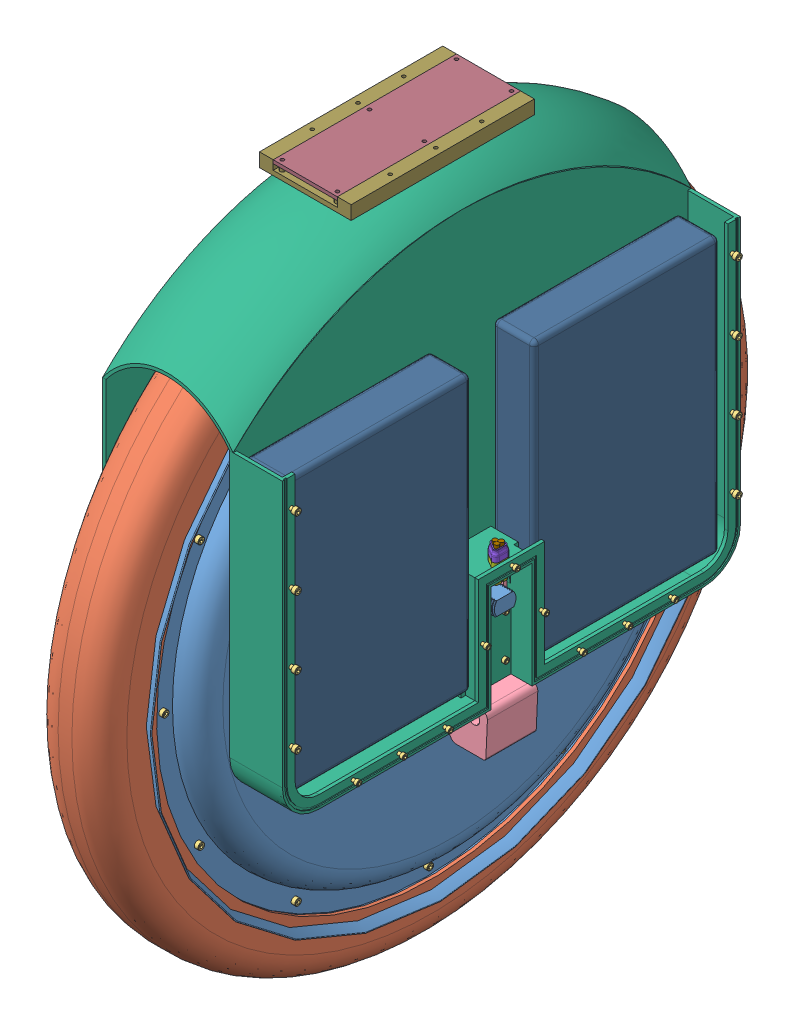
SolidWorks assembly euc0.2, configuration Default. Lengths in mm.
Overall size (364.75 810.04 810.04).
62 component instances, 14 part files, 64 mates.
Components (placement in the parent):
- wheel-1: wheel [Default] at origin size (217.51 810.04 810.04)
  - motor-1: motor [Default] at origin size (188.73 505.83 505.83)
  - tyre-1: tyre [Default] at (-29.8207 0 0) x (1 0 0) z (0 0.587098 0.809516) size (60 580 580)
  - socket head cap screw_ai-1: socket head cap screw_ai [HX-SHCS 0.138-40x0.188x0.188-N] at (29.5052 231 0) x (-1 0 0) z (0 0 -1) size (8.28 5.74 5.74)
  - socket head cap screw_ai-2: socket head cap screw_ai [HX-SHCS 0.138-40x0.188x0.188-N] at (29.5052 200.0519 -115.5) x (-1 0 0) z (0 -0.5 -0.866025) size (8.28 5.74 5.74)
  - socket head cap screw_ai-3: socket head cap screw_ai [HX-SHCS 0.138-40x0.188x0.188-N] at (29.5052 200.0519 115.5) x (-1 0 0) z (0 0.5 -0.866025) size (8.28 5.74 5.74)
  - socket head cap screw_ai-4: socket head cap screw_ai [HX-SHCS 0.138-40x0.188x0.188-N] at (29.5052 115.5 200.0519) x (-1 0 0) z (0 0.866025 -0.5) size (8.28 5.74 5.74)
  - socket head cap screw_ai-5: socket head cap screw_ai [HX-SHCS 0.138-40x0.188x0.188-N] at (29.5052 0 231) x (-1 0 0) z (0 1 0) size (8.28 5.74 5.74)
  - socket head cap screw_ai-6: socket head cap screw_ai [HX-SHCS 0.138-40x0.188x0.188-N] at (29.5052 -115.5 200.0519) x (-1 0 0) z (0 0.866025 0.5) size (8.28 5.74 5.74)
  - socket head cap screw_ai-7: socket head cap screw_ai [HX-SHCS 0.138-40x0.188x0.188-N] at (29.5052 -200.0519 115.5) x (-1 0 0) z (0 0.5 0.866025) size (8.28 5.74 5.74)
  - socket head cap screw_ai-8: socket head cap screw_ai [HX-SHCS 0.138-40x0.188x0.188-N] at (29.5052 -231 0) x (-1 0 0) z (0 0 1) size (8.28 5.74 5.74)
  - socket head cap screw_ai-9: socket head cap screw_ai [HX-SHCS 0.138-40x0.188x0.188-N] at (29.5052 -200.0519 -115.5) x (-1 0 0) z (0 -0.5 0.866025) size (8.28 5.74 5.74)
  - socket head cap screw_ai-10: socket head cap screw_ai [HX-SHCS 0.138-40x0.188x0.188-N] at (29.5052 -115.5 -200.0519) x (-1 0 0) z (0 -0.866025 0.5) size (8.28 5.74 5.74)
  - socket head cap screw_ai-11: socket head cap screw_ai [HX-SHCS 0.138-40x0.188x0.188-N] at (29.5052 0 -231) x (-1 0 0) z (0 -1 0) size (8.28 5.74 5.74)
  - socket head cap screw_ai-12: socket head cap screw_ai [HX-SHCS 0.138-40x0.188x0.188-N] at (29.5052 115.5 -200.0519) x (-1 0 0) z (0 -0.866025 -0.5) size (8.28 5.74 5.74)
  - socket head cap screw_ai-13: socket head cap screw_ai [HX-SHCS 0.138-40x0.188x0.188-N] at (-29.5052 231 0) size (8.28 5.74 5.74)
  - socket head cap screw_ai-14: socket head cap screw_ai [HX-SHCS 0.138-40x0.188x0.188-N] at (-29.5052 200.0519 -115.5) x (1 0 0) z (0 0.5 0.866025) size (8.28 5.74 5.74)
  - socket head cap screw_ai-15: socket head cap screw_ai [HX-SHCS 0.138-40x0.188x0.188-N] at (-29.5052 200.0519 115.5) x (1 0 0) z (0 -0.5 0.866025) size (8.28 5.74 5.74)
  - socket head cap screw_ai-16: socket head cap screw_ai [HX-SHCS 0.138-40x0.188x0.188-N] at (-29.5052 115.5 200.0519) x (1 0 0) z (0 -0.866025 0.5) size (8.28 5.74 5.74)
  - socket head cap screw_ai-17: socket head cap screw_ai [HX-SHCS 0.138-40x0.188x0.188-N] at (-29.5052 0 231) x (1 0 0) z (0 -1 0) size (8.28 5.74 5.74)
  - socket head cap screw_ai-18: socket head cap screw_ai [HX-SHCS 0.138-40x0.188x0.188-N] at (-29.5052 -115.5 200.0519) x (1 0 0) z (0 -0.866025 -0.5) size (8.28 5.74 5.74)
  - socket head cap screw_ai-19: socket head cap screw_ai [HX-SHCS 0.138-40x0.188x0.188-N] at (-29.5052 -200.0519 115.5) x (1 0 0) z (0 -0.5 -0.866025) size (8.28 5.74 5.74)
  - socket head cap screw_ai-20: socket head cap screw_ai [HX-SHCS 0.138-40x0.188x0.188-N] at (-29.5052 -231 0) x (1 0 0) z (0 0 -1) size (8.28 5.74 5.74)
  - socket head cap screw_ai-21: socket head cap screw_ai [HX-SHCS 0.138-40x0.188x0.188-N] at (-29.5052 -200.0519 -115.5) x (1 0 0) z (0 0.5 -0.866025) size (8.28 5.74 5.74)
  - socket head cap screw_ai-22: socket head cap screw_ai [HX-SHCS 0.138-40x0.188x0.188-N] at (-29.5052 -115.5 -200.0519) x (1 0 0) z (0 0.866025 -0.5) size (8.28 5.74 5.74)
  - socket head cap screw_ai-23: socket head cap screw_ai [HX-SHCS 0.138-40x0.188x0.188-N] at (-29.5052 0 -231) x (1 0 0) z (0 1 0) size (8.28 5.74 5.74)
  - socket head cap screw_ai-24: socket head cap screw_ai [HX-SHCS 0.138-40x0.188x0.188-N] at (-29.5052 115.5 -200.0519) x (1 0 0) z (0 0.866025 0.5) size (8.28 5.74 5.74)
  - pedal hanger1-1: pedal hanger1 [Default] at (128.9328 -140.4403 -75.0082) x (0.997537 -0.070149 0) z (-0.006861 -0.09757 0.995205) size (54.31 133.41 56.48)
  - pedal hanger2-1: pedal hanger2 [Default] at (-128.9328 -140.4403 75.0082) x (-0.997537 -0.070149 0) z (0.006861 -0.09757 -0.995205) size (54.31 133.41 56.48)
- Chassis-1: Chassis [Default] at origin size (199.88 371.03 400)
  - Internal chassis-1: Internal chassis [Default] at origin size (181 371.03 400)
- mt60 fem-1: mt60 fem [Default] at (85.5155 -2.714 -4.2673) x (0 1 0) z (0.866025 0 -0.5) size (29 12 12.94)
  - Copy of Мама^mt60 fem-1: Copy of Мама^mt60 fem [По умолчанию] at (18.214 0 0) x (0 0 -1) z (1 0 0) size (12.94 12 20) (virtual)
  - Copy of Колпачек 2^mt60 fem-1: Copy of Колпачек 2^mt60 fem [По умолчанию] at (35.714 0 0) x (0 0 -1) z (1 0 0) size (12.94 12 13) (virtual)
  - Copy of Деталь11^mt60 fem-1: Copy of Деталь11^mt60 fem [По умолчанию] at (44.714 0 0) x (0 0 -1) z (1 0 0) size (8 7.46 6.5) (virtual)
- socket head cap screw_ai-5: socket head cap screw_ai [HX-SHCS 0.112-48x0.188x0.188-N] at (84.3367 -54 12) x (-1 0 0) z (0 0 -1) size (7.62 4.65 4.65)
- socket head cap screw_ai-6: socket head cap screw_ai [HX-SHCS 0.112-48x0.188x0.188-N] at (84.3367 -54 -12) x (-1 0 0) z (0 0 -1) size (7.62 4.65 4.65)
- socket head cap screw_ai-7: socket head cap screw_ai [HX-SHCS 0.112-48x0.188x0.188-N] at (84.3367 -16.951 12) x (-1 0 0) z (0 0 -1) size (7.62 4.65 4.65)
- socket head cap screw_ai-8: socket head cap screw_ai [HX-SHCS 0.112-48x0.188x0.188-N] at (84.3367 -16.951 -12) x (-1 0 0) z (0 0 -1) size (7.62 4.65 4.65)
- Battery-1: Battery [Default] at (75 -52.1123 109.3024) x (0 0 -1) z (1 0 0) size (162 240 36)
- Battery-2: Battery [Default] at (75 -56.3085 -107.6601) x (0 0 -1) z (1 0 0) size (162 240 36)
- Lid^euc0.2-2: Lid^euc0.2 [Default] at (57 0 0) x (0 0 -1) z (1 0 0) size (400 263.96 3) (hidden, virtual)
- socket head cap screw_ai-9: socket head cap screw_ai [HX-SHCS 0.138-40x0.188x0.188-N] at (106.5052 171.9592 192.5) x (-1 0 0) z (0 0 -1) size (8.28 5.74 5.74)
- socket head cap screw_ai-10: socket head cap screw_ai [HX-SHCS 0.138-40x0.188x0.188-N] at (106.5052 111.9592 192.5) x (-1 0 0) z (0 0 -1) size (8.28 5.74 5.74)
- socket head cap screw_ai-11: socket head cap screw_ai [HX-SHCS 0.138-40x0.188x0.188-N] at (106.5052 51.9592 192.5) x (-1 0 0) z (0 0 -1) size (8.28 5.74 5.74)
- socket head cap screw_ai-12: socket head cap screw_ai [HX-SHCS 0.138-40x0.188x0.188-N] at (106.5052 -8.0408 192.5) x (-1 0 0) z (0 0 -1) size (8.28 5.74 5.74)
- socket head cap screw_ai-13: socket head cap screw_ai [HX-SHCS 0.112-48x0.188x0.188-N] at (105.8448 -60.5 58.5) x (-1 0 0) z (0 0 -1) size (7.62 4.65 4.65)
- socket head cap screw_ai-14: socket head cap screw_ai [HX-SHCS 0.112-48x0.188x0.188-N] at (105.8448 -60.5 98.5) x (-1 0 0) z (0 0 -1) size (7.62 4.65 4.65)
- socket head cap screw_ai-15: socket head cap screw_ai [HX-SHCS 0.112-48x0.188x0.188-N] at (105.8448 -60.5 138.5) x (-1 0 0) z (0 0 -1) size (7.62 4.65 4.65)
- socket head cap screw_ai-16: socket head cap screw_ai [HX-SHCS 0.112-48x0.188x0.188-N] at (105.8448 -14 25.5) x (-1 0 0) z (0 0 -1) size (7.62 4.65 4.65)
- socket head cap screw_ai-17: socket head cap screw_ai [HX-SHCS 0.112-48x0.188x0.188-N] at (105.8448 32.5 0) x (-1 0 0) z (0 0 -1) size (7.62 4.65 4.65)
- socket head cap screw_ai-18: socket head cap screw_ai [HX-SHCS 0.112-48x0.188x0.188-N] at (105.8448 -14 -25.5) x (-1 0 0) z (0 0 -1) size (7.62 4.65 4.65)
- socket head cap screw_ai-19: socket head cap screw_ai [HX-SHCS 0.112-48x0.188x0.188-N] at (105.8448 -60.5 -58.5) x (-1 0 0) z (0 0 -1) size (7.62 4.65 4.65)
- socket head cap screw_ai-20: socket head cap screw_ai [HX-SHCS 0.112-48x0.188x0.188-N] at (105.8448 -60.5 -98.5) x (-1 0 0) z (0 0 -1) size (7.62 4.65 4.65)
- socket head cap screw_ai-21: socket head cap screw_ai [HX-SHCS 0.112-48x0.188x0.188-N] at (105.8448 -60.5 -138.5) x (-1 0 0) z (0 0 -1) size (7.62 4.65 4.65)
- socket head cap screw_ai-22: socket head cap screw_ai [HX-SHCS 0.138-40x0.188x0.188-N] at (106.5052 -8.0408 -192.5) x (-1 0 0) z (0 0 -1) size (8.28 5.74 5.74)
- socket head cap screw_ai-23: socket head cap screw_ai [HX-SHCS 0.138-40x0.188x0.188-N] at (106.5052 51.9592 -192.5) x (-1 0 0) z (0 0 -1) size (8.28 5.74 5.74)
- socket head cap screw_ai-24: socket head cap screw_ai [HX-SHCS 0.138-40x0.188x0.188-N] at (106.5052 111.9592 -192.5) x (-1 0 0) z (0 0 -1) size (8.28 5.74 5.74)
- socket head cap screw_ai-25: socket head cap screw_ai [HX-SHCS 0.138-40x0.188x0.188-N] at (106.5052 171.9592 -192.5) x (-1 0 0) z (0 0 -1) size (8.28 5.74 5.74)
- top chassis^euc0.2-1: top chassis^euc0.2 [Default] at origin size (60 14.48 100) (virtual)
- Pcb plate^euc0.2-1: Pcb plate^euc0.2 [Default] at (0 303.0294 0) x (1 0 0) z (0 1 0) size (80 160 12) (virtual)
- pcb^euc0.2-1: pcb^euc0.2 [Default] at (0 312.0294 0) x (1 0 0) z (0 1 0) size (56 160 3) (virtual)
Mates (geometry in assembly coordinates):
- Lock1: lock: unknown of wheel-1/pedal hanger1-1; unknown of Chassis-1/Internal chassis-1
- Parallel1: parallel anti-aligned: plane of Chassis-1/Internal chassis-1 through (0 28 0) normal (0 1 0); plane of mt60 fem-1/Copy of Мама^mt60 fem-1 through (90.0311 15.5 3.5538) normal (0 -1 0)
- Parallel2: parallel aligned: plane of Chassis-1/Internal chassis-1 through (57 28 288) normal (1 0 0); plane of mt60 fem-1/Copy of Мама^mt60 fem-1 through (93 29 3.5538) normal (1 0 0)
- Coincident3: coincident anti-aligned: plane of Chassis-1/Internal chassis-1 through (93 7.266 3.5) normal (-1 0 0); plane of mt60 fem-1/Copy of Мама^mt60 fem-1 through (93 29 3.5538) normal (1 0 0)
- Coincident4: coincident anti-aligned: plane of Chassis-1/Internal chassis-1 through (82.4378 7.266 2.5981) normal (0.5 0 -0.866025); plane of mt60 fem-1/Copy of Мама^mt60 fem-1 through (82.4845 29 2.625) normal (-0.5 0 0.866025)
- Coincident5: coincident aligned: plane of Chassis-1/Internal chassis-1 through (100 25 0) normal (0 -1 0); plane of mt60 fem-1/Copy of Мама^mt60 fem-1 through (83.9689 25 0.0538) normal (0 -1 0)
- Concentric51: concentric aligned: cylinder of Chassis-1/Internal chassis-1 through (73.7574 -54 12) axis (1 0 0) radius 1.5; cylinder of socket head cap screw_ai-5 through (116.0867 -54 12) axis (1 0 0) radius 1.4224
- Coincident101: coincident anti-aligned: plane of Chassis-1/Internal chassis-1 through (81.4919 -65.951 -74.1577) normal (1 0 0); plane of socket head cap screw_ai-5 through (81.4919 -51.6759 12) normal (-1 0 0)
- Concentric61: concentric aligned: cylinder of Chassis-1/Internal chassis-1 through (73.7574 -54 -12) axis (1 0 0) radius 1.5; cylinder of socket head cap screw_ai-6 through (116.0867 -54 -12) axis (1 0 0) radius 1.4224
- Coincident111: coincident anti-aligned: plane of Chassis-1/Internal chassis-1 through (81.4919 -65.951 -74.1577) normal (1 0 0); plane of socket head cap screw_ai-6 through (81.4919 -51.6759 -12) normal (-1 0 0)
- Concentric71: concentric aligned: cylinder of Chassis-1/Internal chassis-1 through (73.7574 -16.951 12) axis (1 0 0) radius 1.5; cylinder of socket head cap screw_ai-7 through (116.0867 -16.951 12) axis (1 0 0) radius 1.4224
- Coincident121: coincident anti-aligned: plane of Chassis-1/Internal chassis-1 through (81.4919 -65.951 -74.1577) normal (1 0 0); plane of socket head cap screw_ai-7 through (81.4919 -14.6269 12) normal (-1 0 0)
- Concentric81: concentric aligned: cylinder of Chassis-1/Internal chassis-1 through (73.7574 -16.951 -12) axis (1 0 0) radius 1.5; cylinder of socket head cap screw_ai-8 through (116.0867 -16.951 -12) axis (1 0 0) radius 1.4224
- Coincident131: coincident anti-aligned: plane of Chassis-1/Internal chassis-1 through (81.4919 -65.951 -74.1577) normal (1 0 0); plane of socket head cap screw_ai-8 through (81.4919 -14.6269 -12) normal (-1 0 0)
- Coincident18: coincident anti-aligned: plane of Chassis-1/Internal chassis-1 through (57 28 288) normal (1 0 0); plane of Battery1-1 through (57 187.8877 190.3024) normal (-1 0 0)
- Coincident23: coincident anti-aligned: plane of Chassis-1/Internal chassis-1 through (57 28 288) normal (1 0 0); plane of Battery2-2 through (57 212.7697 -24.9641) normal (-1 0 0)
- Parallel5: parallel aligned: plane of Chassis-1/Internal chassis-1 through (0 28 0) normal (0 1 0); plane of Battery1-1 through (75 187.8877 109.3024) normal (0 1 0)
- Parallel6: parallel aligned: plane of Chassis-1/Internal chassis-1 through (0 28 0) normal (0 1 0); plane of Battery2-2 through (75 212.7697 -105.9641) normal (0 1 0)
- InPlace2: in place: plane of ? through (57 28 288) normal (1 0 0); plane of Lid^euc0.2-2 through (57 0 0) normal (1 0 0); moOrthogonalPlaneRef_w of ? through (57 28 288) normal (1 0 0); plane of Lid^euc0.2-2 through (57 0 0) normal (0 1 0); plane of ? through (57 28 288) normal (1 0 0); plane of Lid^euc0.2-2 through (57 0 0) normal (0 0 -1); plane of ? through (57 28 288) normal (1 0 0); unknown of Lid^euc0.2-2
- Coincident26: coincident aligned: plane of Chassis-1/Internal chassis-1; plane of Lid^euc0.2-2
- Coincident27: coincident aligned: moOrthogonalPlaneRef_w of Chassis-1/Internal chassis-1 through (57 0 0) normal (0 1 0); plane of Lid^euc0.2-2 through (57 0 0) normal (0 1 0)
- Coincident28: coincident anti-aligned: moOrthogonalPlaneRef_w of Chassis-1/Internal chassis-1 through (57 0 0) normal (0 0 1); plane of Lid^euc0.2-2 through (57 0 0) normal (0 0 -1)
- Concentric821: concentric aligned: cylinder of Lid^euc0.2-2 through (94.9868 171.9592 192.5) axis (1 0 0) radius 1.7724; cylinder of socket head cap screw_ai-9 through (138.2552 171.9592 192.5) axis (1 0 0) radius 1.7526
- Coincident1321: coincident anti-aligned: plane of Lid^euc0.2-2 through (103 -36 -168) normal (1 0 0); plane of socket head cap screw_ai-9 through (103 174.8294 192.5) normal (-1 0 0)
- Concentric831: concentric aligned: cylinder of Lid^euc0.2-2 through (94.9868 111.9592 192.5) axis (1 0 0) radius 1.7724; cylinder of socket head cap screw_ai-10 through (138.2552 111.9592 192.5) axis (1 0 0) radius 1.7526
- Coincident1331: coincident anti-aligned: plane of Lid^euc0.2-2 through (103 -36 -168) normal (1 0 0); plane of socket head cap screw_ai-10 through (103 114.8294 192.5) normal (-1 0 0)
- Concentric841: concentric aligned: cylinder of Lid^euc0.2-2 through (94.9868 51.9592 192.5) axis (1 0 0) radius 1.7724; cylinder of socket head cap screw_ai-11 through (138.2552 51.9592 192.5) axis (1 0 0) radius 1.7526
- Coincident1341: coincident anti-aligned: plane of Lid^euc0.2-2 through (103 -36 -168) normal (1 0 0); plane of socket head cap screw_ai-11 through (103 54.8294 192.5) normal (-1 0 0)
- Concentric851: concentric aligned: cylinder of Lid^euc0.2-2 through (94.9868 -8.0408 192.5) axis (1 0 0) radius 1.7724; cylinder of socket head cap screw_ai-12 through (138.2552 -8.0408 192.5) axis (1 0 0) radius 1.7526
- Coincident1351: coincident anti-aligned: plane of Lid^euc0.2-2 through (103 -36 -168) normal (1 0 0); plane of socket head cap screw_ai-12 through (103 -5.1706 192.5) normal (-1 0 0)
- Concentric861: concentric aligned: cylinder of Lid^euc0.2-2 through (94.9868 -60.5 58.5) axis (1 0 0) radius 1.5; cylinder of socket head cap screw_ai-13 through (137.5948 -60.5 58.5) axis (1 0 0) radius 2.3241
- Coincident1361: coincident anti-aligned: plane of Lid^euc0.2-2 through (103 -36 -168) normal (1 0 0); plane of socket head cap screw_ai-13 through (103 -58.1759 58.5) normal (-1 0 0)
- Concentric871: concentric aligned: cylinder of Lid^euc0.2-2 through (94.9868 -60.5 98.5) axis (1 0 0) radius 1.5; cylinder of socket head cap screw_ai-14 through (137.5948 -60.5 98.5) axis (1 0 0) radius 2.3241
- Coincident1371: coincident anti-aligned: plane of Lid^euc0.2-2 through (103 -36 -168) normal (1 0 0); plane of socket head cap screw_ai-14 through (103 -58.1759 98.5) normal (-1 0 0)
- Concentric881: concentric aligned: cylinder of Lid^euc0.2-2 through (94.9868 -60.5 138.5) axis (1 0 0) radius 1.5; cylinder of socket head cap screw_ai-15 through (137.5948 -60.5 138.5) axis (1 0 0) radius 2.3241
- Coincident1381: coincident anti-aligned: plane of Lid^euc0.2-2 through (103 -36 -168) normal (1 0 0); plane of socket head cap screw_ai-15 through (103 -58.1759 138.5) normal (-1 0 0)
- Concentric891: concentric aligned: cylinder of Lid^euc0.2-2 through (94.9868 -14 25.5) axis (1 0 0) radius 1.5; cylinder of socket head cap screw_ai-16 through (137.5948 -14 25.5) axis (1 0 0) radius 2.3241
- Coincident1391: coincident anti-aligned: plane of Lid^euc0.2-2 through (103 -36 -168) normal (1 0 0); plane of socket head cap screw_ai-16 through (103 -11.6759 25.5) normal (-1 0 0)
- Concentric901: concentric aligned: cylinder of Lid^euc0.2-2 through (94.9868 32.5 0) axis (1 0 0) radius 1.5; cylinder of socket head cap screw_ai-17 through (137.5948 32.5 0) axis (1 0 0) radius 2.3241
- Coincident1401: coincident anti-aligned: plane of Lid^euc0.2-2 through (103 -36 -168) normal (1 0 0); plane of socket head cap screw_ai-17 through (103 34.8241 0) normal (-1 0 0)
- Concentric911: concentric aligned: cylinder of Lid^euc0.2-2 through (94.9868 -14 -25.5) axis (1 0 0) radius 1.5; cylinder of socket head cap screw_ai-18 through (137.5948 -14 -25.5) axis (1 0 0) radius 2.3241
- Coincident1411: coincident anti-aligned: plane of Lid^euc0.2-2 through (103 -36 -168) normal (1 0 0); plane of socket head cap screw_ai-18 through (103 -11.6759 -25.5) normal (-1 0 0)
- Concentric921: concentric aligned: cylinder of Lid^euc0.2-2 through (94.9868 -60.5 -58.5) axis (1 0 0) radius 1.5; cylinder of socket head cap screw_ai-19 through (137.5948 -60.5 -58.5) axis (1 0 0) radius 2.3241
- Coincident1421: coincident anti-aligned: plane of Lid^euc0.2-2 through (103 -36 -168) normal (1 0 0); plane of socket head cap screw_ai-19 through (103 -58.1759 -58.5) normal (-1 0 0)
- Concentric931: concentric aligned: cylinder of Lid^euc0.2-2 through (94.9868 -60.5 -98.5) axis (1 0 0) radius 1.5; cylinder of socket head cap screw_ai-20 through (137.5948 -60.5 -98.5) axis (1 0 0) radius 2.3241
- Coincident1431: coincident anti-aligned: plane of Lid^euc0.2-2 through (103 -36 -168) normal (1 0 0); plane of socket head cap screw_ai-20 through (103 -58.1759 -98.5) normal (-1 0 0)
- Concentric941: concentric aligned: cylinder of Lid^euc0.2-2 through (94.9868 -60.5 -138.5) axis (1 0 0) radius 1.5; cylinder of socket head cap screw_ai-21 through (137.5948 -60.5 -138.5) axis (1 0 0) radius 2.3241
- Coincident1441: coincident anti-aligned: plane of Lid^euc0.2-2 through (103 -36 -168) normal (1 0 0); plane of socket head cap screw_ai-21 through (103 -58.1759 -138.5) normal (-1 0 0)
- Concentric951: concentric aligned: cylinder of Lid^euc0.2-2 through (94.9868 -8.0408 -192.5) axis (1 0 0) radius 1.7724; cylinder of socket head cap screw_ai-22 through (138.2552 -8.0408 -192.5) axis (1 0 0) radius 1.7526
- Coincident1451: coincident anti-aligned: plane of Lid^euc0.2-2 through (103 -36 -168) normal (1 0 0); plane of socket head cap screw_ai-22 through (103 -5.1706 -192.5) normal (-1 0 0)
- Concentric961: concentric aligned: cylinder of Lid^euc0.2-2 through (94.9868 51.9592 -192.5) axis (1 0 0) radius 1.7724; cylinder of socket head cap screw_ai-23 through (138.2552 51.9592 -192.5) axis (1 0 0) radius 1.7526
- Coincident1461: coincident anti-aligned: plane of Lid^euc0.2-2 through (103 -36 -168) normal (1 0 0); plane of socket head cap screw_ai-23 through (103 54.8294 -192.5) normal (-1 0 0)
- Concentric971: concentric aligned: cylinder of Lid^euc0.2-2 through (94.9868 111.9592 -192.5) axis (1 0 0) radius 1.7724; cylinder of socket head cap screw_ai-24 through (138.2552 111.9592 -192.5) axis (1 0 0) radius 1.7526
- Coincident1471: coincident anti-aligned: plane of Lid^euc0.2-2 through (103 -36 -168) normal (1 0 0); plane of socket head cap screw_ai-24 through (103 114.8294 -192.5) normal (-1 0 0)
- Concentric981: concentric aligned: cylinder of Lid^euc0.2-2 through (94.9868 171.9592 -192.5) axis (1 0 0) radius 1.7724; cylinder of socket head cap screw_ai-25 through (138.2552 171.9592 -192.5) axis (1 0 0) radius 1.7526
- Coincident1481: coincident anti-aligned: plane of Lid^euc0.2-2 through (103 -36 -168) normal (1 0 0); plane of socket head cap screw_ai-25 through (103 174.8294 -192.5) normal (-1 0 0)
- InPlace3: in place: plane of ? through (0 303.0294 0) normal (0 1 0); plane of Pcb plate^euc0.2-1 through (0 303.0294 0) normal (0 1 0); plane of ? through (0 303.0294 0) normal (0 1 0); plane of Pcb plate^euc0.2-1 through (0 303.0294 0) normal (0 0 -1); plane of ? through (0 303.0294 0) normal (0 1 0); plane of Pcb plate^euc0.2-1 through (0 303.0294 0) normal (1 0 0); plane of ? through (0 303.0294 0) normal (0 1 0); unknown of Pcb plate^euc0.2-1
- Coincident1482: coincident aligned: plane of top chassis^euc0.2-1; plane of Pcb plate^euc0.2-1
- Coincident1483: coincident aligned: moOrthogonalPlaneRef_w of top chassis^euc0.2-1 through (0 303.0294 0) normal (0 0 -1); plane of Pcb plate^euc0.2-1 through (0 303.0294 0) normal (0 0 -1)
- Coincident1484: coincident anti-aligned: moOrthogonalPlaneRef_w of top chassis^euc0.2-1 through (0 303.0294 0) normal (-1 0 0); plane of Pcb plate^euc0.2-1 through (0 303.0294 0) normal (1 0 0)
- Coincident1488: coincident anti-aligned: plane of Pcb plate^euc0.2-1 through (-24 312.0294 76) normal (0 1 0); plane of pcb^euc0.2-1 through (0 312.0294 0) normal (0 -1 0)
- Coincident1489: coincident aligned: plane of Pcb plate^euc0.2-1 through (-40 307.0294 80) normal (0 0 1); plane of pcb^euc0.2-1 through (-28 315.0294 80) normal (0 0 1)
- Coincident1490: coincident anti-aligned: plane of Pcb plate^euc0.2-1 through (28 315.0294 -80) normal (-1 0 0); plane of pcb^euc0.2-1 through (28 315.0294 80) normal (1 0 0)
- Coincident1491: coincident anti-aligned: plane of Chassis-1/Internal chassis-1 through (57 28 288) normal (1 0 0); plane of Battery-2 through (57 183.6915 -26.6601) normal (-1 0 0)
